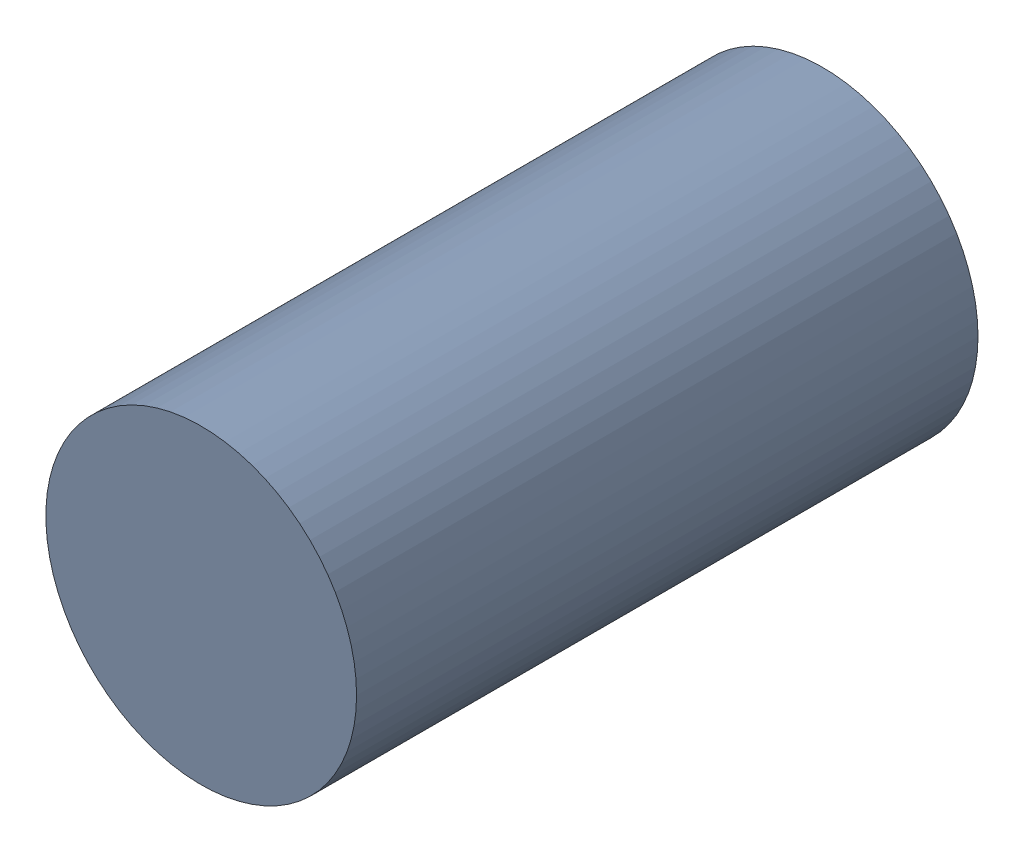
SolidWorks assembly MH10_1.step, configuration Default. Lengths in mm.
Overall size (1 1 2).
2 component instances, 1 part files, 0 mates.
Components (placement in the parent):
- 9228463120_1.step-3: 9228463120_1.step [Default] at (365.9996 301.0003 -1.5) size (1 1 2)
  - Cylinder_1.step-26: Cylinder_1.step [Default] at origin size (1 1 2)
